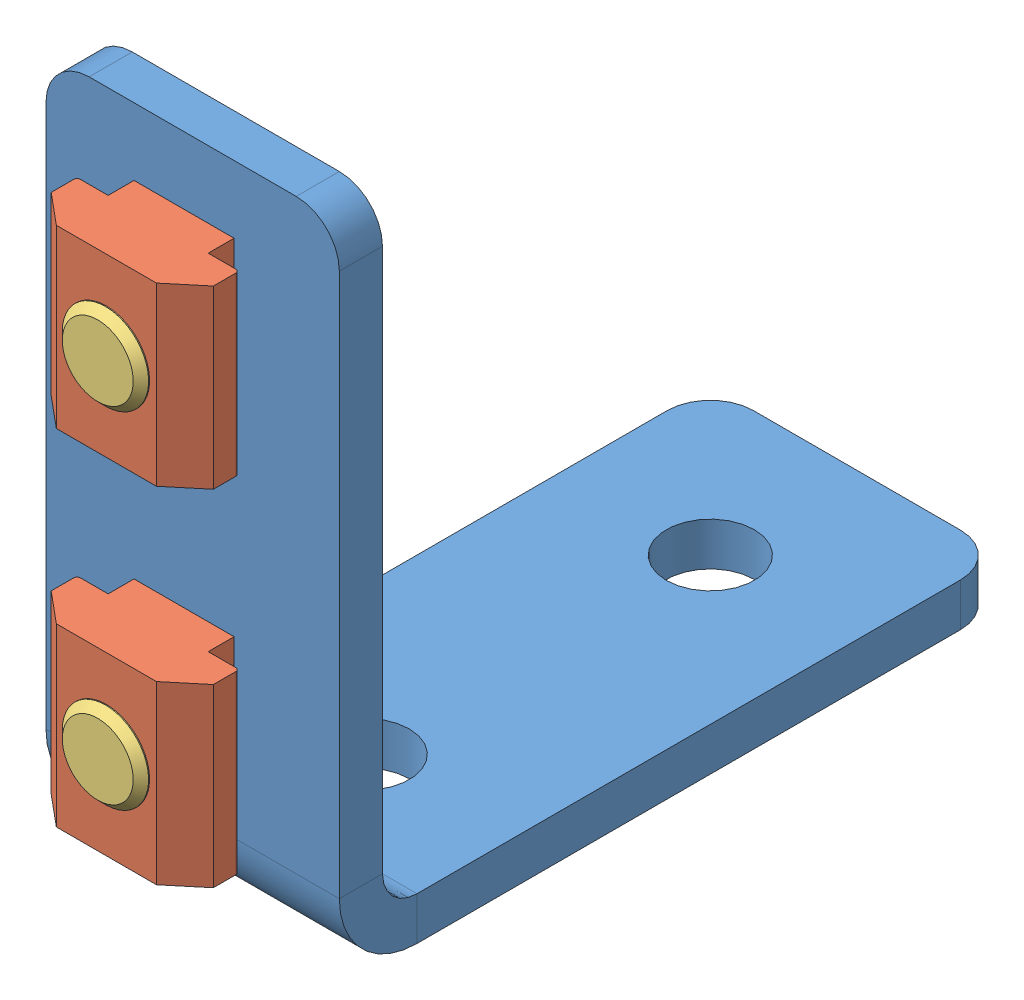
SolidWorks assembly AssemblyCorner, configuration Default. Lengths in mm.
Overall size (17 38.5 44).
5 component instances, 3 part files, 13 mates.
Components (placement in the parent):
- Corner Bracket 40х20L-1: Corner Bracket 40х20L [Default] at (-8.5 0 0) size (17 38.5 38.5)
- T nut 2020 М5-1: T nut 2020 М5 [Default] at (0 35.1 5) x (0 -1 0) z (1 0 0) size (10.2 4.5 9.4)
- head screw ISO 7380 M5 x 8-1: head screw ISO 7380 M5 x 8 [Default] at (0 30 -5.25) x (0 0 1) z (-1 0 0) size (10.75 9.5 9.5)
- head screw ISO 7380 M5 x 8-2: head screw ISO 7380 M5 x 8 [Default] at (0 10 -5.25) x (0 0 1) z (-1 0 0) size (10.75 9.5 9.5)
- T nut 2020 М5-2: T nut 2020 М5 [Default] at (0 15.1 5) x (0 -1 0) z (1 0 0) size (10.2 4.5 9.4)
Mates (geometry in assembly coordinates):
- Symmetric1: symmetric aligned: plane of Corner Bracket 40х40L-1 through (8.5 2.5 -4.5) normal (1 0 0); plane of Corner Bracket 40х40L-1 through (-8.5 4.5 -4.5) normal (-1 0 0); plane of assembly through (0 0 0) normal (1 0 0)
- Coincident1: coincident: plane of Corner Bracket 40х40L-1 through (8.5 0 0) normal (0 -1 0)
- Coincident2: coincident: plane of Corner Bracket 40х40L-1 through (8.5 0 0) normal (0 0 1)
- Coincident3: coincident aligned: plane of Corner Bracket 40х40L-1 through (8.5 0 0) normal (0 0 1); plane of assembly through (0 0 0) normal (0 0 1)
- Coincident4: coincident anti-aligned: plane of Corner Bracket 40х40L-1 through (8.5 0 -2.5) normal (0 0 -1); plane of head screw ISO 7380 M5 x 8-1 through (0 32.5 -2.5) normal (0 0 1)
- Concentric1: concentric anti-aligned: cylinder of T nut 2020 М5-1 through (0 30 10.7) axis (0 0 -1) radius 2.5; cylinder of head screw ISO 7380 M5 x 8-1 through (0 30 -8.8935) axis (0 0 1) radius 2.5
- Concentric2: concentric anti-aligned: cylinder of Corner Bracket 40х40L-1 through (0 30 0) axis (0 0 -1) radius 2.55; cylinder of head screw ISO 7380 M5 x 8-1 through (0 30 -8.8935) axis (0 0 1) radius 2.5
- Parallel1: parallel aligned: plane of Corner Bracket 40х40L-1 through (8.5 38.5 0) normal (0 1 0); plane of T nut 2020 М5-1 through (0 35.1 5) normal (0 1 0)
- Distance1: distance = 2 mm anti-aligned: plane of Corner Bracket 40х40L-1 through (8.5 0 0) normal (0 0 1); plane of T nut 2020 М5-1 through (4.7 24.9 2) normal (0 0 -1)
- Concentric31: concentric anti-aligned: cylinder of Corner Bracket 40х40L-1 through (0 10 0) axis (0 0 -1) radius 2.55; cylinder of head screw ISO 7380 M5 x 8-2 through (0 10 -8.8935) axis (0 0 1) radius 4.75
- Coincident51: coincident anti-aligned: plane of Corner Bracket 40х40L-1 through (8.5 0 -2.5) normal (0 0 -1); plane of head screw ISO 7380 M5 x 8-2 through (0 12.5 -2.5) normal (0 0 1)
- Concentric6: concentric anti-aligned: cylinder of head screw ISO 7380 M5 x 8-2 through (0 10 -8.8935) axis (0 0 1) radius 2.5; cylinder of T nut 2020 М5-2 through (0 10 10.7) axis (0 0 -1) radius 2.5
- Distance2: distance = 2 mm anti-aligned: plane of Corner Bracket 40х40L-1 through (8.5 0 0) normal (0 0 1); plane of T nut 2020 М5-2 through (4.7 4.9 2) normal (0 0 -1)
